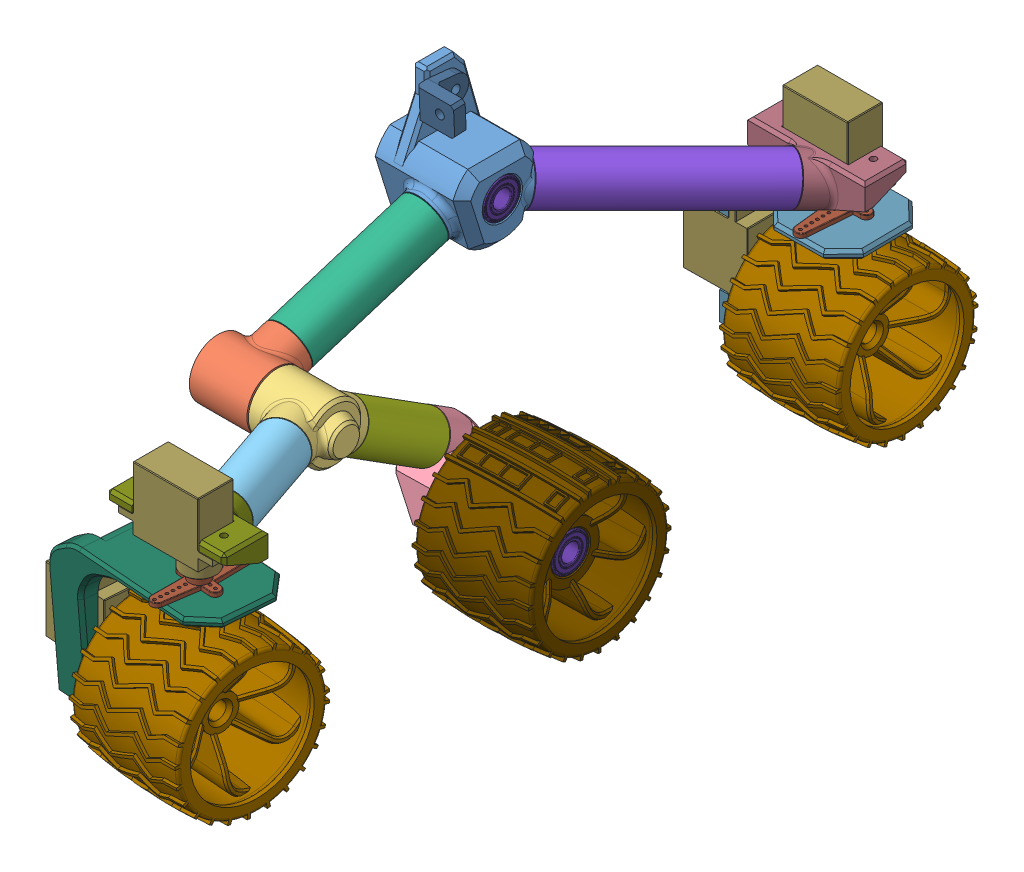
SolidWorks assembly suspensionSub-right[moving], configuration Default. Lengths in mm.
Overall size (94.81 134.77 289.93).
30 component instances, 18 part files, 67 mates.
Components (placement in the parent):
- rockerJoint-right-1: rockerJoint-right [Default] at (-2.7999 34.0109 38.9762) x (1 0 0) z (0 -0.297904 0.954596) size (35.64 50.55 55.79)
- bogieJointFixed-right-1: bogieJointFixed-right [Default] at (4.7001 10.2318 115.1719) x (0 0.297904 -0.954596) z (1 0.000031 0.00001) size (40 20 21.53)
- bogieJointFree-right-1: bogieJointFree-right [Default] at (25.2001 10.2325 115.1721) x (1 0.000031 0.00001) z (-0.000025 0.534634 0.845084) size (27.04 27.37 57.25)
- wheelStrut-mid-left-1: wheelStrut-mid-left [Default] at (35.3595 -30.576 69.7904) x (0.999881 0.013064 -0.008236) z (0.008236 0.000041 0.999966) size (23.13 36.67 28.96)
- aftBogieTube-1: aftBogieTube [Default] at (54.6139 14.8068 163.3357) x (0.909041 0.166061 -0.382188) z (-0.18696 0.982204 -0.017919) size (15.88 37.13 15.88)
- aftRockerTube-1: aftRockerTube [Default] at (14.7001 14.7007 100.8531) x (1 0.000031 0.00001) z (-0.000033 0.954596 0.297904) size (15.88 49.82 15.88)
- foreBogieTube-1: foreBogieTube [Default] at (35.2013 -15.8039 74.0166) x (0.99896 -0.038524 0.024401) z (-0.045602 -0.844205 0.534077) size (15.88 33.7 15.88)
- foreRockerTube-1: foreRockerTube [Default] at (53.0095 15.8862 -35.7528) x (0.835794 0.445925 0.320312) z (0.320312 -0.869851 0.375178) size (15.88 70.91 15.88)
- tire-1: tire [Default] at (60.2 -30.577 177.1943) x (0.016798 -0.976378 -0.215417) z (0.996973 0 0.077744) size (53.45 55.85 40.12)
- tire-3: tire [Default] at (59.6984 -30.5783 -48.8006) x (0.000553 -0.99885 0.047945) z (0.999934 0 -0.011529) size (53.45 55.85 40.12)
- rodHinge-sus-1: rodHinge-sus [Default] at (8.2001 34.0425 37.8861) x (0 0.339249 -0.940697) z (1 0 0) size (15.98 12.99 13)
- sg90ServoHorn-star-1: sg90ServoHorn-star [Default] at (39.7296 -32.8229 -45.9828) x (0.001455 0.992001 0.12622) z (0.011437 -0.126229 0.991935) size (34.4 4 15.7)
- sg90Servo-1: sg90Servo [Default] at (9.8644 -36.327 167.1005) x (0 1 0) z (0.077744 0 -0.996973) size (32.7 29.37 12.3)
- sg90Servo-2: sg90Servo [Default] at (65.4484 35.3897 -42.6506) x (-1 0 0) z (0 0 1) size (32.7 29.37 12.3)
- sg90Servo-3: sg90Servo [Default] at (8.6629 -36.3283 -54.3625) x (0 1 0) z (-0.011529 0 -0.999934) size (32.7 29.37 12.3)
- sg90Servo-4: sg90Servo [Default] at (65.95 35.391 183.3444) x (-1 0 -0.000013) z (-0.000013 0 1) size (32.7 29.37 12.3)
- wheelPivot-front-right-v2-1: wheelPivot-front-right-v2 [Default] at (65.4484 35.3897 -42.6506) x (-1 0 0) z (0 0 1) size (40.7 16.47 34.17)
- wheelStrut-front-right-v2-1: wheelStrut-front-right-v2 [Default] at (8.6629 -36.3283 -54.3625) x (0 1 0) z (-0.011529 0 -0.999934) size (50.75 59.16 31.22)
- sg90ServoHorn-star-2: sg90ServoHorn-star [Default] at (62.5701 4.4217 -46.9335) x (-0.011529 0 -0.999934) z (0.999934 0 -0.011529) size (34.4 4 15.7)
- sg90ServoHorn-star-3: sg90ServoHorn-star [Default] at (40.1123 -33.4223 177.5407) x (-0.029724 0.924024 0.381177) z (-0.071837 -0.382334 0.921227) size (34.4 4 15.7)
- sg90ServoHorn-star-4: sg90ServoHorn-star [Default] at (57.5064 4.423 175.0785) x (-0.077744 0 0.996973) z (-0.996973 0 -0.077744) size (34.4 4 15.7)
- wheelStrut-rear-right-v2-1: wheelStrut-rear-right-v2 [Default] at (8.9082 -36.327 179.3633) x (0 1 0) z (0.077744 0 -0.996973) size (50.75 59.16 31.22)
- wheelPivot-rear-right-v2-1: wheelPivot-rear-right-v2 [Default] at (65.9501 35.391 171.0444) x (1 0 0.000013) z (0.000013 0 -1) size (40.7 18.75 35.49)
- 6x13x5BearingShielded-1: 6x13x5BearingShielded [Default] at (22.2001 34.0109 38.9762) x (0 -1 0) z (0 0 1) size (13 5 13)
- 6x13x5BearingShielded-2: 6x13x5BearingShielded [Default] at (2.2001 34.0109 38.9762) x (0 1 0) z (0 0 1) size (13 5 13)
- 6x13x5BearingShielded-3: 6x13x5BearingShielded [Default] at (24.7001 10.2325 115.1721) x (-0.000031 1 0) z (-0.00001 0 1) size (13 5 13)
- 6x13x5BearingShielded-4: 6x13x5BearingShielded [Default] at (9.7001 10.232 115.1719) x (-0.000031 1 0) z (-0.00001 0 1) size (13 5 13)
- tire-mid-1: tire-mid [Default] at (71.3839 -30.1053 69.4937) x (-0.008063 -0.013171 -0.999881) z (0.999881 0.013064 -0.008236) size (53.45 55.85 40.12)
- 6x13x5BearingShielded-5: 6x13x5BearingShielded [Default] at (56.3856 -30.3013 69.6172) x (0.013171 -0.999828 0.013064) z (-0.008063 -0.013171 -0.999881) size (13 5 13)
- 6x13x5BearingShielded-6: 6x13x5BearingShielded [Default] at (76.3833 -30.04 69.4525) x (0.013171 -0.999828 0.013064) z (0.008063 0.013171 0.999881) size (13 5 13)
Mates (geometry in assembly coordinates):
- Concentric1: concentric aligned: line of rockerJoint-right-1 through (14.7001 34.0109 38.9762) axis (0.445925 -0.210972 -0.869851); cylinder of foreRockerTube-1 through (21.389 30.8463 25.9284) axis (0.445925 -0.210972 -0.869851) radius 7.94
- Coincident2: coincident anti-aligned: plane of rockerJoint-right-1 through (21.389 30.8463 25.9284) normal (0.445925 -0.210972 -0.869851); plane of foreRockerTube-1 through (21.389 30.8463 25.9284) normal (-0.445925 0.210972 0.869851)
- Concentric2: concentric anti-aligned: line of rockerJoint-right-1 through (14.7001 9.6207 117.1313) axis (0 0.297904 -0.954596); cylinder of aftRockerTube-1 through (14.7001 29.5423 53.2951) axis (0 -0.297904 0.954596) radius 7.94
- Coincident3: coincident anti-aligned: plane of rockerJoint-right-1 through (14.7001 29.5423 53.2951) normal (0 -0.297904 0.954596); plane of aftRockerTube-1 through (14.7001 29.5423 53.2951) normal (0 0.297904 -0.954596)
- Concentric4: concentric aligned: line of bogieJointFixed-right-1 through (14.7001 14.7007 100.8531) axis (0 -0.297904 0.954596); cylinder of aftRockerTube-1 through (14.7001 29.5423 53.2951) axis (0 -0.297904 0.954596) radius 7.94
- Coincident5: coincident anti-aligned: plane of bogieJointFixed-right-1 through (14.7001 14.7007 100.8531) normal (0 0.297904 -0.954596); plane of aftRockerTube-1 through (14.7001 14.7007 100.8531) normal (0 -0.297904 0.954596)
- Distance9: distance = 0.5 mm anti-aligned: plane of bogieJointFixed-right-1 through (24.7001 10.2325 115.1721) normal (1 0.000031 0.00001); plane of bogieJointFree-right-1 through (25.2001 10.2325 115.1721) normal (-1 -0.000031 -0.00001)
- Concentric5: concentric aligned: cylinder of bogieJointFixed-right-1 through (24.7001 10.2325 115.1721) axis (-1 -0.000031 -0.00001) radius 10; cylinder of bogieJointFree-right-1 through (45.2001 10.2331 115.1723) axis (-1 -0.000031 -0.00001) radius 10
- Concentric6: concentric aligned: line of bogieJointFree-right-1 through (35.2001 10.2328 115.1722) axis (0.000025 -0.534634 -0.845084); cylinder of foreBogieTube-1 through (35.2005 2.2133 102.4959) axis (0.000025 -0.534634 -0.845084) radius 7.94
- Coincident7: coincident anti-aligned: plane of bogieJointFree-right-1 through (35.2005 2.2133 102.4959) normal (0.000025 -0.534634 -0.845084); plane of foreBogieTube-1 through (35.2005 2.2133 102.4959) normal (-0.000025 0.534634 0.845084)
- Concentric7: concentric aligned: line of wheelStrut-mid-left-1 through (35.2001 10.2324 115.1715) axis (0.000025 -0.534634 -0.845084); cylinder of foreBogieTube-1 through (35.2005 2.2133 102.4959) axis (0.000025 -0.534634 -0.845084) radius 7.94
- Coincident8: coincident anti-aligned: plane of wheelStrut-mid-left-1 through (35.2013 -15.8039 74.0166) normal (-0.000025 0.534634 0.845084); plane of foreBogieTube-1 through (35.2013 -15.8039 74.0166) normal (0.000025 -0.534634 -0.845084)
- Concentric8: concentric anti-aligned: line of bogieJointFree-right-1 through (60.1993 16.1228 177.1925) axis (-0.372411 -0.087743 -0.923911); cylinder of aftBogieTube-1 through (40.7863 11.5489 129.0309) axis (0.372411 0.087743 0.923911) radius 7.94
- Coincident9: coincident anti-aligned: plane of bogieJointFree-right-1 through (40.7863 11.5489 129.0309) normal (0.372411 0.087743 0.923911); plane of aftBogieTube-1 through (40.7863 11.5489 129.0309) normal (-0.372411 -0.087743 -0.923911)
- Distance8: distance = 1 mm anti-aligned: plane of rockerJoint-right-1 through (7.2001 39.9288 53.1212) normal (1 0 0); plane of rodHinge-sus-1 through (8.2001 34.0425 37.8861) normal (-1 0 0)
- Concentric18: concentric anti-aligned: cylinder of rockerJoint-right-1 through (-2.8009 59.0109 39.1571) axis (1 0 0) radius 1.55; cylinder of rodHinge-sus-1 through (11.2001 59.0109 39.1571) axis (-1 0 0) radius 1.55
- Coincident30: coincident anti-aligned: plane of tire-3 through (39.713 -54.5482 -47.4194) normal (-0.999934 0 0.011529); plane of sg90ServoHorn-star-1 through (39.7296 -32.8229 -45.9828) normal (0.999934 0 -0.011529)
- Concentric19: concentric anti-aligned: line of tire-3 through (37.6999 -30.5783 -48.5469) axis (0.999934 0 -0.011529); cylinder of sg90ServoHorn-star-1 through (39.7007 -30.5783 -48.57) axis (-0.999934 0 0.011529) radius 1.2
- Coincident31: coincident anti-aligned: plane of sg90ServoHorn-star-1 through (38.0998 -30.5783 -48.5515) normal (-0.999934 0 0.011529); plane of sg90Servo-3 through (38.0998 -30.5783 -48.5515) normal (0.999934 0 -0.011529)
- Concentric20: concentric aligned: cylinder of sg90ServoHorn-star-1 through (38.0998 -30.5783 -48.5515) axis (-0.999934 0 0.011529) radius 2.4; cylinder of sg90Servo-3 through (38.0998 -30.5783 -48.5515) axis (-0.999934 0 0.011529) radius 1.984
- Concentric21: concentric aligned: cylinder of foreRockerTube-1 through (21.389 30.8463 25.9284) axis (0.445925 -0.210972 -0.869851) radius 7.94; cylinder of wheelPivot-front-right-v2-1 through (53.0095 15.8862 -35.7528) axis (0.445925 -0.210972 -0.869851) radius 7.94
- Coincident32: coincident anti-aligned: plane of foreRockerTube-1 through (53.0095 15.8862 -35.7528) normal (0.445925 -0.210972 -0.869851); plane of wheelPivot-front-right-v2-1 through (53.0095 15.8862 -35.7528) normal (-0.445925 0.210972 0.869851)
- Parallel1: parallel aligned: plane of rockerJoint-right-1 through (27.2011 46.0109 38.9762) normal (0 1 0); plane of wheelPivot-front-right-v2-1 through (65.4484 22.7647 -39.6506) normal (0 1 0)
- Coincident34: coincident aligned: line of sg90Servo-3 through (24.4258 -36.5783 -42.4935) axis (-0.011529 0 -0.999934); line of wheelStrut-front-right-v2-1 through (24.4287 -36.5783 -42.2435) axis (-0.011529 0 -0.999934)
- Coincident35: coincident anti-aligned: plane of sg90Servo-3 through (30.8864 -36.3283 -54.6188) normal (-0.011529 0 -0.999934); plane of wheelStrut-front-right-v2-1 through (8.6629 -36.3283 -54.3625) normal (0.011529 0 0.999934)
- Coincident38: coincident anti-aligned: line of sg90Servo-3 through (24.2897 -13.3783 -54.2927) axis (0.011529 0 0.999934); line of wheelStrut-front-right-v2-1 through (24.4287 -13.3783 -42.2435) axis (-0.011529 0 -0.999934)
- Coincident39: coincident anti-aligned: plane of sg90Servo-2 through (65.4484 13.1647 -42.6506) normal (0 0 1); plane of wheelPivot-front-right-v2-1 through (65.4484 35.3897 -42.6506) normal (0 0 -1)
- Coincident40: coincident aligned: line of sg90Servo-2 through (65.6984 19.7647 -54.7006) axis (0 0 1); line of wheelPivot-front-right-v2-1 through (65.6984 19.7647 -54.9506) axis (0 0 1)
- Coincident43: coincident anti-aligned: line of sg90Servo-2 through (42.4984 19.7647 -42.9006) axis (0 0 -1); line of wheelPivot-front-right-v2-1 through (42.4984 19.7647 -54.9506) axis (0 0 1)
- Concentric25: concentric aligned: cylinder of wheelStrut-front-right-v2-1 through (59.6984 -46.3294 -48.8006) axis (0 1 0) radius 2.4; cylinder of sg90ServoHorn-star-2 through (59.6984 4.4207 -48.8006) axis (0 1 0) radius 1.2
- Coincident44: coincident anti-aligned: plane of wheelStrut-front-right-v2-1 through (8.5822 4.4217 -61.362) normal (0 1 0); plane of sg90ServoHorn-star-2 through (62.5701 4.4217 -46.9335) normal (0 -1 0)
- Concentric26: concentric aligned: cylinder of sg90Servo-2 through (59.6984 6.0217 -48.8006) axis (0 1 0) radius 1.984; cylinder of sg90ServoHorn-star-2 through (59.6984 6.0217 -48.8006) axis (0 1 0) radius 2.4
- Coincident46: coincident anti-aligned: plane of sg90Servo-2 through (59.6984 6.0217 -48.8006) normal (0 -1 0); plane of sg90ServoHorn-star-2 through (59.6984 6.0217 -48.8006) normal (0 1 0)
- Coincident47: coincident anti-aligned: plane of tire-1 through (40.6637 -54.0076 170.47) normal (-0.996973 0 -0.077744); plane of sg90ServoHorn-star-3 through (40.1123 -33.4223 177.5407) normal (0.996973 0 0.077744)
- Concentric27: concentric anti-aligned: line of tire-1 through (38.2666 -30.577 175.484) axis (0.996973 0 0.077744); cylinder of sg90ServoHorn-star-3 through (40.2616 -30.577 175.6395) axis (-0.996973 0 -0.077744) radius 1.2
- Coincident48: coincident anti-aligned: plane of sg90Servo-1 through (38.6654 -30.577 175.5151) normal (0.996973 0 0.077744); plane of sg90ServoHorn-star-3 through (38.6654 -30.577 175.5151) normal (-0.996973 0 -0.077744)
- Concentric28: concentric aligned: cylinder of sg90Servo-1 through (38.6654 -30.577 175.5151) axis (-0.996973 0 -0.077744) radius 1.984; cylinder of sg90ServoHorn-star-3 through (38.6654 -30.577 175.5151) axis (-0.996973 0 -0.077744) radius 2.4
- Coincident49: coincident aligned: line of sg90Servo-1 through (25.4227 -13.377 168.5645) axis (-0.077744 0 0.996973); line of wheelStrut-rear-right-v2-1 through (25.4421 -13.377 168.3152) axis (-0.077744 0 0.996973)
- Coincident53: coincident anti-aligned: line of sg90Servo-1 through (24.5053 -36.577 180.3288) axis (0.077744 0 -0.996973); line of wheelStrut-rear-right-v2-1 through (25.4421 -36.577 168.3152) axis (-0.077744 0 0.996973)
- Coincident54: coincident anti-aligned: plane of sg90Servo-1 through (31.0659 -36.327 181.0911) normal (-0.077744 0 0.996973); plane of wheelStrut-rear-right-v2-1 through (8.9082 -36.327 179.3633) normal (0.077744 0 -0.996973)
- Concentric29: concentric aligned: cylinder of aftBogieTube-1 through (40.7863 11.5489 129.0309) axis (0.372411 0.087743 0.923911) radius 7.94; cylinder of wheelPivot-rear-right-v2-1 through (54.6139 14.8068 163.3357) axis (0.372411 0.087743 0.923911) radius 7.94
- Coincident55: coincident anti-aligned: plane of aftBogieTube-1 through (54.6139 14.8068 163.3357) normal (0.372411 0.087743 0.923911); plane of wheelPivot-rear-right-v2-1 through (54.6139 14.8068 163.3357) normal (-0.372411 -0.087743 -0.923911)
- Coincident57: coincident anti-aligned: line of sg90Servo-4 through (66.2001 19.766 171.2944) axis (-0.000013 0 1); line of wheelPivot-rear-right-v2-1 through (66.2 19.766 183.3444) axis (0.000013 0 -1)
- Coincident58: coincident aligned: line of sg90Servo-4 through (43 19.766 183.0941) axis (0.000013 0 -1); line of wheelPivot-rear-right-v2-1 through (43 19.766 183.3441) axis (0.000013 0 -1)
- Coincident59: coincident anti-aligned: plane of sg90Servo-4 through (65.9501 13.166 171.0444) normal (0.000013 0 -1); plane of wheelPivot-rear-right-v2-1 through (65.9501 35.391 171.0444) normal (-0.000013 0 1)
- Coincident60: coincident anti-aligned: plane of sg90ServoHorn-star-4 through (57.5064 4.423 175.0785) normal (0 -1 0); plane of wheelStrut-rear-right-v2-1 through (8.364 4.423 186.3421) normal (0 1 0)
- Concentric31: concentric aligned: cylinder of sg90ServoHorn-star-4 through (60.2 4.422 177.1943) axis (0 1 0) radius 1.2; cylinder of wheelStrut-rear-right-v2-1 through (60.2 -46.3281 177.1943) axis (0 1 0) radius 2.4
- Concentric32: concentric aligned: cylinder of sg90Servo-4 through (60.2 6.023 177.1943) axis (0 1 0) radius 1.984; cylinder of sg90ServoHorn-star-4 through (60.2 6.023 177.1943) axis (0 1 0) radius 2.4
- Coincident62: coincident anti-aligned: plane of sg90Servo-4 through (60.2 6.023 177.1943) normal (0 -1 0); plane of sg90ServoHorn-star-4 through (60.2 6.023 177.1943) normal (0 1 0)
- Concentric33: concentric anti-aligned: cylinder of rockerJoint-right-1 through (3.2001 34.0109 38.9762) axis (-1 0 0) radius 6.5; cylinder of 6x13x5BearingShielded-2 through (-2.7999 34.0109 38.9762) axis (1 0 0) radius 6.5
- Coincident63: coincident aligned: plane of rockerJoint-right-1 through (-2.7999 34.0109 38.9762) normal (-1 0 0); plane of 6x13x5BearingShielded-2 through (-2.7999 34.0109 38.9762) normal (-1 0 0)
- Concentric34: concentric anti-aligned: cylinder of rockerJoint-right-1 through (21.2001 34.0109 38.9762) axis (1 0 0) radius 6.5; cylinder of 6x13x5BearingShielded-1 through (27.2001 34.0109 38.9762) axis (-1 0 0) radius 6.5
- Coincident64: coincident aligned: plane of rockerJoint-right-1 through (27.2001 34.0109 38.9762) normal (1 0 0); plane of 6x13x5BearingShielded-1 through (27.2001 34.0109 38.9762) normal (1 0 0)
- Concentric35: concentric anti-aligned: cylinder of bogieJointFixed-right-1 through (10.7001 10.232 115.172) axis (-1 -0.000031 -0.00001) radius 6.5; cylinder of 6x13x5BearingShielded-4 through (4.7001 10.2318 115.1719) axis (1 0.000031 0.00001) radius 6.5
- Coincident65: coincident aligned: plane of bogieJointFixed-right-1 through (4.7001 10.2318 115.1719) normal (-1 -0.000031 -0.00001); plane of 6x13x5BearingShielded-4 through (4.7001 10.2318 115.1719) normal (-1 -0.000031 -0.00001)
- Concentric36: concentric aligned: cylinder of bogieJointFixed-right-1 through (18.7001 10.2323 115.172) axis (1 0.000031 0.00001) radius 6.5; cylinder of 6x13x5BearingShielded-3 through (19.7001 10.2323 115.172) axis (1 0.000031 0.00001) radius 6.5
- Coincident66: coincident aligned: plane of bogieJointFixed-right-1 through (24.7001 10.2325 115.1721) normal (1 0.000031 0.00001); plane of 6x13x5BearingShielded-3 through (24.7001 10.2325 115.1721) normal (1 0.000031 0.00001)
- Concentric37: concentric anti-aligned: cylinder of tire-mid-1 through (57.3855 -30.2882 69.609) axis (-0.999881 -0.013064 0.008236) radius 6.5; cylinder of 6x13x5BearingShielded-5 through (51.3862 -30.3666 69.6584) axis (0.999881 0.013064 -0.008236) radius 6.5
- Coincident67: coincident aligned: plane of tire-mid-1 through (51.1927 -30.6827 45.6638) normal (-0.999881 -0.013064 0.008236); plane of 6x13x5BearingShielded-5 through (51.3862 -30.3666 69.6584) normal (-0.999881 -0.013064 0.008236)
- Concentric38: concentric anti-aligned: cylinder of tire-mid-1 through (75.3834 -30.0531 69.4607) axis (0.999881 0.013064 -0.008236) radius 6.5; cylinder of 6x13x5BearingShielded-6 through (81.3827 -29.9747 69.4113) axis (-0.999881 -0.013064 0.008236) radius 6.5
- Coincident68: coincident aligned: plane of tire-mid-1 through (81.3827 -29.9747 69.4113) normal (0.999881 0.013064 -0.008236); plane of 6x13x5BearingShielded-6 through (81.3827 -29.9747 69.4113) normal (0.999881 0.013064 -0.008236)
- Concentric39: concentric aligned: cylinder of wheelStrut-mid-left-1 through (22.4725 -30.7444 69.8965) axis (0.999881 0.013064 -0.008236) radius 3; cylinder of tire-mid-1 through (51.3265 -30.3674 69.6589) axis (0.999881 0.013064 -0.008236) radius 3.75
- Distance10: distance = 1 mm anti-aligned: plane of tire-mid-1 through (51.1927 -30.6827 45.6638) normal (-0.999881 -0.013064 0.008236); plane of wheelStrut-mid-left-1 through (50.4687 -30.3793 79.6663) normal (0.999881 0.013064 -0.008236)
- Concentric40: concentric aligned: cylinder of tire-3 through (50.0914 -45.4584 -50.5833) axis (-0.999934 0 0.011529) radius 0.5; cylinder of sg90ServoHorn-star-1 through (39.6789 -45.4584 -50.4633) axis (-0.999934 0 0.011529) radius 0.5
- Concentric41: concentric aligned: cylinder of tire-1 through (51.0891 -44.4374 170.7314) axis (-0.996973 0 -0.077744) radius 0.5; cylinder of sg90ServoHorn-star-3 through (40.7074 -44.4374 169.9219) axis (-0.996973 0 -0.077744) radius 0.5
- Concentric42: concentric aligned: cylinder of wheelStrut-front-right-v2-1 through (59.8022 -46.3294 -39.8012) axis (0 1 0) radius 0.5; cylinder of sg90ServoHorn-star-2 through (59.8022 4.4207 -39.8012) axis (0 1 0) radius 0.5
- Concentric43: concentric aligned: cylinder of sg90ServoHorn-star-4 through (60.8997 4.422 168.2216) axis (0 1 0) radius 0.5; cylinder of wheelStrut-rear-right-v2-1 through (60.8997 -46.3281 168.2216) axis (0 1 0) radius 0.5
